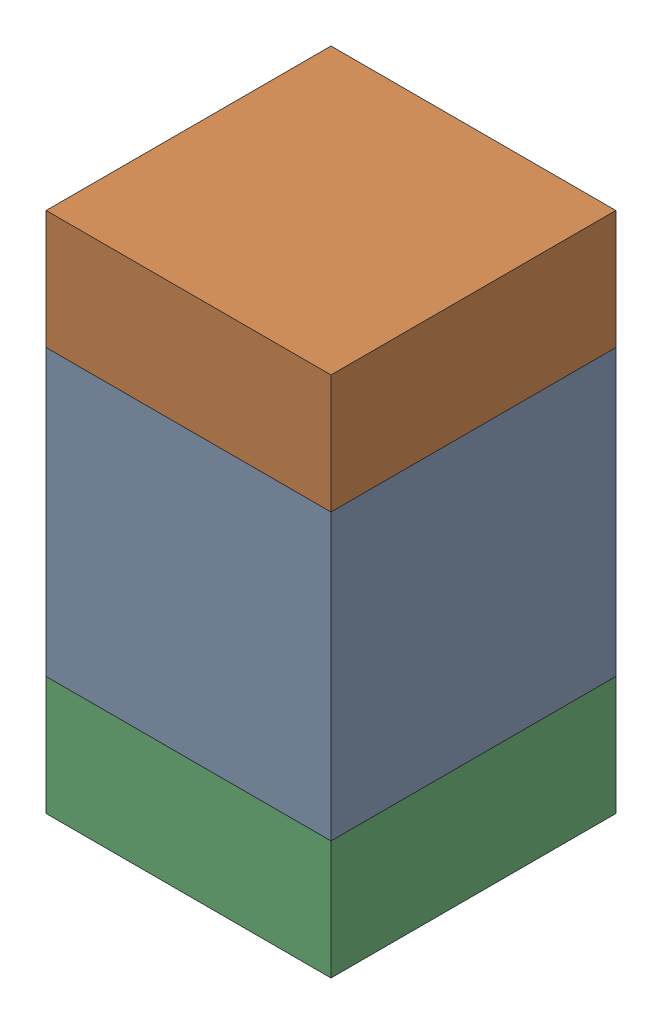
SolidWorks assembly C124_1PCB, configuration Default. Lengths in mm.
Overall size (0.6 1.1 0.6).
6 component instances, 2 part files, 0 mates.
Components (placement in the parent):
- 761606048-1: 761606048 [Default] at (105.3 121.3 0) size (0.6 0.6 0.6)
  - Extruded_9-1: Extruded_9 [Default] at origin size (0.6 0.6 0.6)
- 854785296-1: 854785296 [Default] at (105.3 121.725 0) size (0.6 0.25 0.6)
  - Extruded_10-1: Extruded_10 [Default] at origin size (0.6 0.25 0.6)
- 854785296-2: 854785296 [Default] at (105.3 120.875 0) size (0.6 0.25 0.6)
  - Extruded_10-1: Extruded_10 [Default] at origin size (0.6 0.25 0.6)
